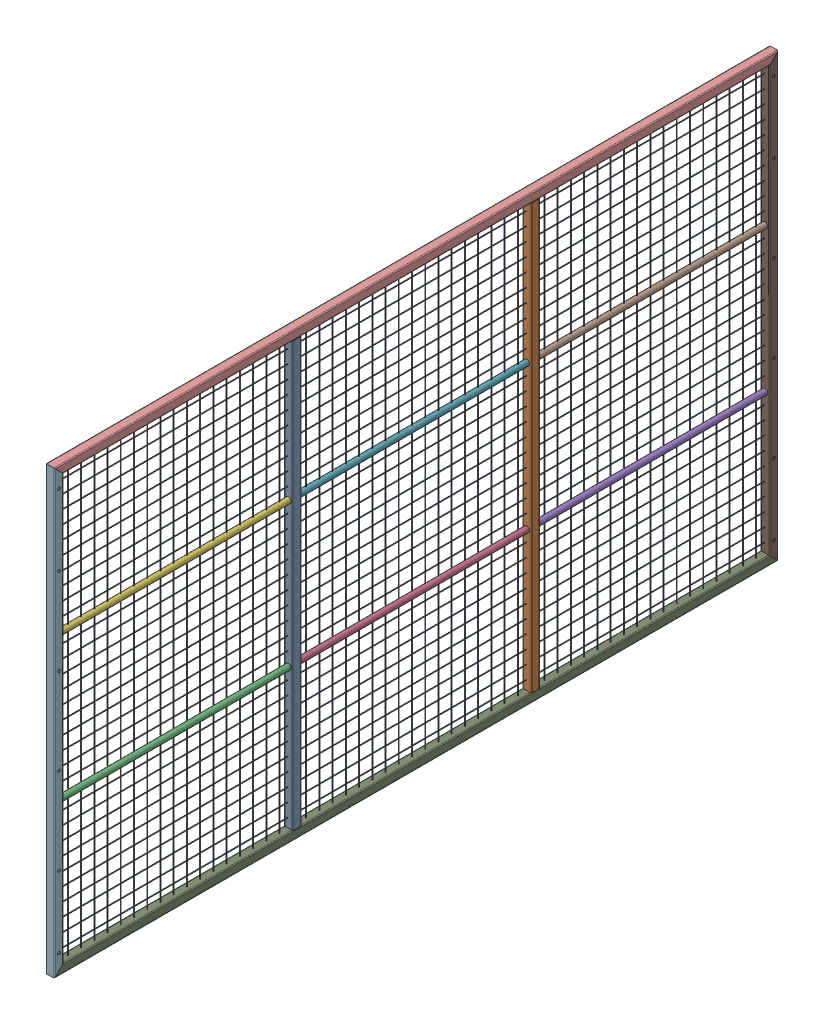
SolidWorks assembly 02.01.00_Värav_külg_koost, configuration Default. Lengths in mm.
Overall size (40 2002 3280).
21 component instances, 5 part files, 6 mates.
Components (placement in the parent):
- 02.01.02_Nkt_40x40x2_S235_1922-1: 02.01.02_Nkt_40x40x2_S235_1922 [Default] at origin size (40 1922 40)
- 02.01.02_Nkt_40x40x2_S235_1922-2: 02.01.02_Nkt_40x40x2_S235_1922 [Default] at (0 0 -1080) size (40 1922 40)
- 02.01.03_Toru_25x1.5_S235_1040-1: 02.01.03_Toru_25x1.5_S235_1040 [Default] at origin size (25 25 1040)
- 02.01.03_Toru_25x1.5_S235_1040-2: 02.01.03_Toru_25x1.5_S235_1040 [Default] at (0 0 -1080) size (25 25 1040)
- 02.01.03_Toru_25x1.5_S235_1040-3: 02.01.03_Toru_25x1.5_S235_1040 [Default] at (0 0 -2160) size (25 25 1040)
- 02.01.03_Toru_25x1.5_S235_1040-4: 02.01.03_Toru_25x1.5_S235_1040 [Default] at (0 654 0) size (25 25 1040)
- 02.01.03_Toru_25x1.5_S235_1040-5: 02.01.03_Toru_25x1.5_S235_1040 [Default] at (0 654 -1080) size (25 25 1040)
- 02.01.03_Toru_25x1.5_S235_1040-6: 02.01.03_Toru_25x1.5_S235_1040 [Default] at (0 654 -2160) size (25 25 1040)
- 02.01.04_Nkt_40x40x2_S235_3280-1: 02.01.04_Nkt_40x40x2_S235_3280 [Default] at origin size (40 40 3280)
- 02.01.04_Nkt_40x40x2_S235_3280-2: 02.01.04_Nkt_40x40x2_S235_3280 [Default] at (0 1962 0) x (-1 0 0) z (0 0 1) size (40 40 3280)
- 02.01.05_Nkt_40x40x2_S235_2002-1: 02.01.05_Nkt_40x40x2_S235_2002 [Default] at origin size (40 2002 40)
- 02.01.05_Nkt_40x40x2_S235_2002-2: 02.01.05_Nkt_40x40x2_S235_2002 [Default] at (0 0 -3240) x (-1 0 0) z (0 0 -1) size (40 2002 40)
- 02.01.01_Võrk_1040x621.5x3_S235-1: 02.01.01_Võrk_1040x621.5x3_S235 [Default] at (-3 0 2160) size (6 621.5 1040)
- 02.01.01_Võrk_1040x621.5x3_S235-10: 02.01.01_Võrk_1040x621.5x3_S235 [Default] at (-3 654 2160) size (6 621.5 1040)
- 02.01.01_Võrk_1040x621.5x3_S235-4: 02.01.01_Võrk_1040x621.5x3_S235 [Default] at (-3 0 1080) size (6 621.5 1040)
- 02.01.01_Võrk_1040x621.5x3_S235-7: 02.01.01_Võrk_1040x621.5x3_S235 [Default] at (-3 0 0) size (6 621.5 1040)
- 02.01.01_Võrk_1040x621.5x3_S235-13: 02.01.01_Võrk_1040x621.5x3_S235 [Default] at (-3 1300.48 2160) size (6 621.5 1040)
- 02.01.01_Võrk_1040x621.5x3_S235-14: 02.01.01_Võrk_1040x621.5x3_S235 [Default] at (-3 1300.48 1080) size (6 621.5 1040)
- 02.01.01_Võrk_1040x621.5x3_S235-15: 02.01.01_Võrk_1040x621.5x3_S235 [Default] at (-3 1300.48 0) size (6 621.5 1040)
- 02.01.01_Võrk_1040x621.5x3_S235-11: 02.01.01_Võrk_1040x621.5x3_S235 [Default] at (-3 654 1080) size (6 621.5 1040)
- 02.01.01_Võrk_1040x621.5x3_S235-12: 02.01.01_Võrk_1040x621.5x3_S235 [Default] at (-3 654 0) size (6 621.5 1040)
Mates (geometry in assembly coordinates):
- Coincident1: coincident anti-aligned: plane of 02.01.04_Nkt_40x40x2_S235_3280-1 through (-15.5 20 -3240) normal (0 1 0); plane of 02.01.01_Võrk_1040x621.5x3_S235-1 through (0 20 -60) normal (0 -1 0)
- Coincident2: coincident anti-aligned: plane of 02.01.05_Nkt_40x40x2_S235_2002-2 through (15.5 1962 -20) normal (0 0 -1); plane of 02.01.01_Võrk_1040x621.5x3_S235-1 through (17.01 641.5 -20) normal (0 0 1)
- Distance1: distance = 18.5 mm: cylinder of 02.01.01_Võrk_1040x621.5x3_S235-1 through (0 1982.002 -120) axis (0 -1 0) radius 1.5; plane of 02.01.04_Nkt_40x40x2_S235_3280-1 through (20 -15.5 -3240) normal (1 0 0)
- Concentric1: concentric aligned: cylinder of 02.01.01_Võrk_1040x621.5x3_S235-1 through (0 1982.002 -60) axis (0 -1 0) radius 1.5; cylinder of 02.01.01_Võrk_1040x621.5x3_S235-10 through (0 2636.002 -60) axis (0 -1 0) radius 1.5
- Concentric2: concentric aligned: cylinder of 02.01.01_Võrk_1040x621.5x3_S235-1 through (0 1982.002 -1020) axis (0 -1 0) radius 1.5; cylinder of 02.01.01_Võrk_1040x621.5x3_S235-10 through (0 2636.002 -1020) axis (0 -1 0) radius 1.5
- Tangent2: tangent anti-aligned: cylinder of 02.01.03_Toru_25x1.5_S235_1040-4 through (0 1308 -3240) axis (0 0 1) radius 12.5; plane of 02.01.01_Võrk_1040x621.5x3_S235-10 through (17.01 1295.5 -1060) normal (0 1 0)
